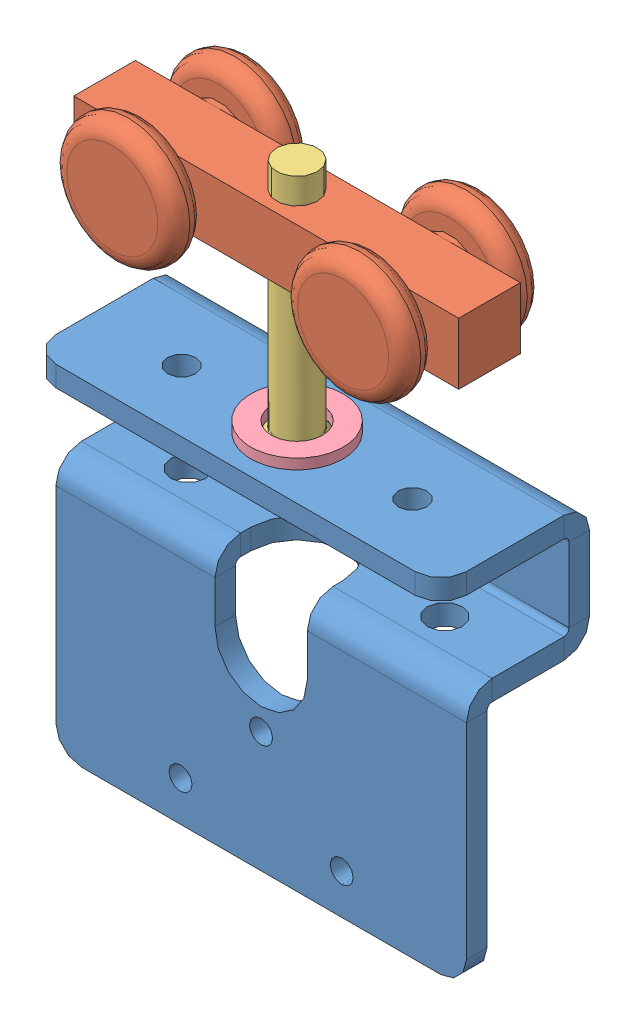
SolidWorks assembly B20-2K--1, configuration Default. Lengths in mm.
Overall size (80 117.5 30.5).
4 component instances, 4 part files, 0 mates.
Components (placement in the parent):
- G2311(Default)--1: G2311(Default)- [Default] at origin size (80 70.5 29)
- G2029--1: G2029- [Default] at (0 59.5 -3) x (0 0 -1) z (1 0 0) size (27 24 75)
- G2316(B18.3.5M - 8 x 1.25 x 50 Socket FCHS  -- 28S)--1: G2316(B18.3.5M - 8 x 1.25 x 50 Socket FCHS  -- 28S)- [Default] at (0 20.5 -3) x (0 1 0) z (-0.922323 0 0.386419) size (50 15.5 15.5)
- BRB-10x18x2--1: BRB-10x18x2- [Default] at (0 24.5 -3) size (18 2 18)
